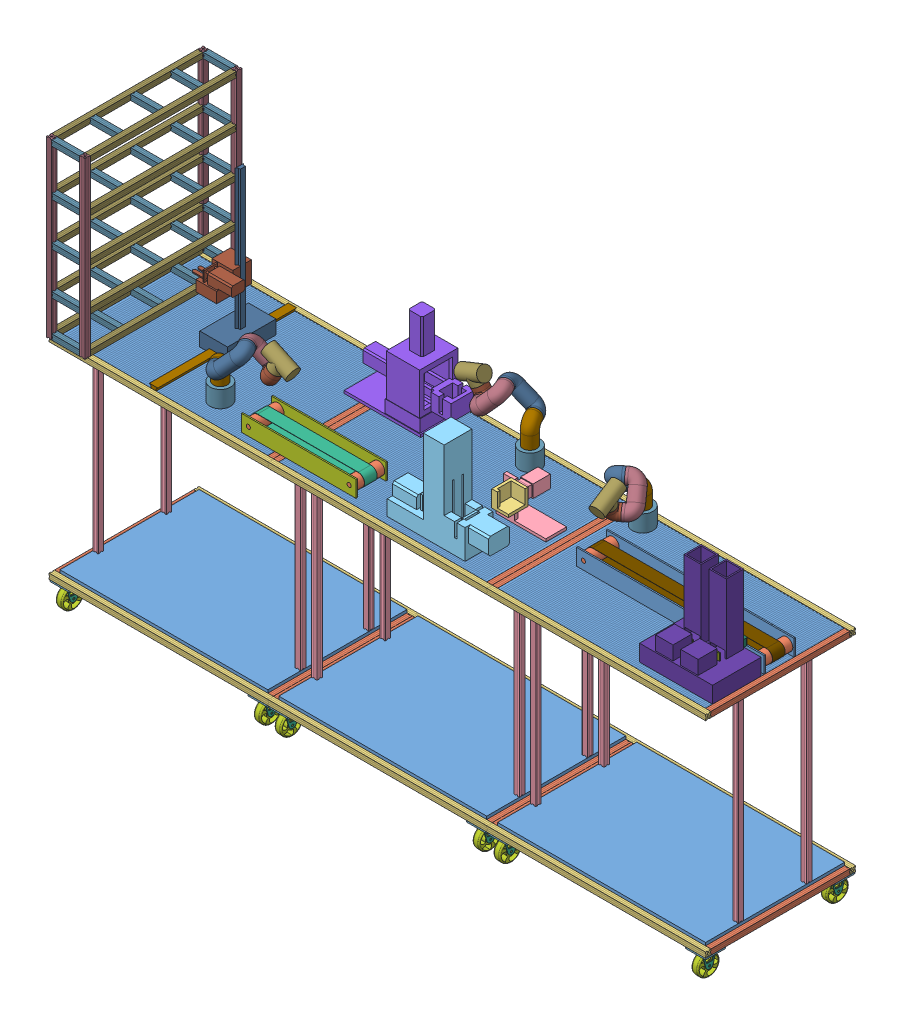
SolidWorks assembly FinalSchematic, configuration Default. Lengths in mm.
Overall size (2780.43 1698.52 1073.82).
241 component instances, 32 part files, 32 mates.
Components (placement in the parent):
- Table1-1: Table1 [Default] at (306.3244 -25.8546 100.2971) size (800.1 872.37 567.56)
  - Aluminium_Platform-1: Aluminium_Platform [Default] at (-670.8382 851.0101 977.8823) size (760.1 30.48 508.64)
  - Aluminium_Extrusion_20_03-1: Aluminium_Extrusion_20_03 [Default] at (109.2618 881.4901 978.0043) x (0 -1 0) z (1 0 0) size (20 508.76 20)
  - Aluminium_Extrusion_20_03-2: Aluminium_Extrusion_20_03 [Default] at (-670.8382 881.4901 978.0043) x (0 -1 0) z (1 0 0) size (20 508.76 20)
  - Aluminium_Extrusion_31_5-1: Aluminium_Extrusion_31_5 [Default] at (109.2618 881.4901 469.2423) x (0 0 -1) z (0 1 0) size (20 800.1 20)
  - Aluminium_Extrusion_31_5-2: Aluminium_Extrusion_31_5 [Default] at (-690.8382 861.4901 977.8823) x (0 1 0) z (0 0 -1) size (20 800.1 20)
  - Aluminium_Extrusion_28-1: Aluminium_Extrusion_28 [Default] at (69.2618 139.8101 858.1823) size (20 711.2 20)
  - Aluminium_Extrusion_28-2: Aluminium_Extrusion_28 [Default] at (69.2618 139.8101 608.9423) size (20 711.2 20)
  - Aluminium_Extrusion_28-3: Aluminium_Extrusion_28 [Default] at (-670.8382 139.8101 858.1823) size (20 711.2 20)
  - Aluminium_Extrusion_28-4: Aluminium_Extrusion_28 [Default] at (-670.8382 139.8101 608.9423) size (20 711.2 20)
  - Aluminium_Extrusion_31_5-3: Aluminium_Extrusion_31_5 [Default] at (-690.8382 129.3301 469.2423) x (0 -1 0) z (0 0 1) size (20 800.1 20)
  - Aluminium_Extrusion_31_5-4: Aluminium_Extrusion_31_5 [Default] at (109.2618 109.3301 977.8823) x (0 0 1) z (0 -1 0) size (20 800.1 20)
  - Aluminium_Extrusion_20_03-3: Aluminium_Extrusion_20_03 [Default] at (-670.8382 109.3301 469.1203) x (0 1 0) z (1 0 0) size (20 508.76 20)
  - Aluminium_Extrusion_20_03-4: Aluminium_Extrusion_20_03 [Default] at (109.2618 109.3301 469.1203) x (0 1 0) z (1 0 0) size (20 508.76 20)
  - Aluminium_Platform-2: Aluminium_Platform [Default] at (-670.8382 139.8101 469.2423) x (1 0 0) z (0 0 -1) size (760.1 30.48 508.64)
  - Assem1-1: Assem1 [Default] at (6.3509 58.2726 926.429) size (76.2 100.21 95.12)
    - Part1-1: Part1 [Default] at (64.8109 45.9775 33.3533) size (76.2 5.08 76.2)
    - Part2-1: Part2 [Default] at (64.8109 38.3575 33.3533) x (-0.998094 0 -0.06171) z (0.06171 0 -0.998094) size (30.99 63.5 50.8)
    - Part3-1: Part3 [Default] at (52.1351 -2.2825 32.5696) x (0.998094 0 0.06171) z (0.059483 -0.266209 -0.962078) size (25.4 76.2 76.2)
    - Part5-1: Part5 [Default] at (65.2258 -8.5737 26.6431) size (6.35 6.35 6.35)
    - Part5-2: Part5 [Default] at (65.3084 2.1674 25.3079) x (0.997369 0.05869 0.042559) z (0.042559 -0.949244 0.311648) size (6.35 6.35 6.35)
    - Part5-3: Part5 [Default] at (64.7035 6.7588 35.0912) x (0.993111 0.036272 0.111421) z (0.111421 -0.586665 -0.802128) size (6.35 6.35 6.35)
    - Part5-4: Part5 [Default] at (64.2471 -1.1445 42.4728) x (0.993111 -0.036272 0.111421) z (0.111421 0.586665 -0.802128) size (6.35 6.35 6.35)
    - Part5-5: Part5 [Default] at (64.5699 -10.6206 37.2516) x (0.997369 -0.05869 0.042559) z (0.042559 0.949244 0.311648) size (6.35 6.35 6.35)
  - Assem1-2: Assem1 [Default] at (-717.5491 58.2726 926.429) size (76.2 100.21 95.12)
    - Part1-1: Part1 [Default] at (64.8109 45.9775 33.3533) size (76.2 5.08 76.2)
    - Part2-1: Part2 [Default] at (64.8109 38.3575 33.3533) x (-0.998094 0 -0.06171) z (0.06171 0 -0.998094) size (30.99 63.5 50.8)
    - Part3-1: Part3 [Default] at (52.1351 -2.2825 32.5696) x (0.998094 0 0.06171) z (0.059483 -0.266209 -0.962078) size (25.4 76.2 76.2)
    - Part5-1: Part5 [Default] at (65.2258 -8.5737 26.6431) size (6.35 6.35 6.35)
    - Part5-2: Part5 [Default] at (65.3084 2.1674 25.3079) x (0.997369 0.05869 0.042559) z (0.042559 -0.949244 0.311648) size (6.35 6.35 6.35)
    - Part5-3: Part5 [Default] at (64.7035 6.7588 35.0912) x (0.993111 0.036272 0.111421) z (0.111421 -0.586665 -0.802128) size (6.35 6.35 6.35)
    - Part5-4: Part5 [Default] at (64.2471 -1.1445 42.4728) x (0.993111 -0.036272 0.111421) z (0.111421 0.586665 -0.802128) size (6.35 6.35 6.35)
    - Part5-5: Part5 [Default] at (64.5699 -10.6206 37.2516) x (0.997369 -0.05869 0.042559) z (0.042559 0.949244 0.311648) size (6.35 6.35 6.35)
  - Assem1-3: Assem1 [Default] at (-717.5491 58.2726 453.989) size (76.2 100.21 95.12)
    - Part1-1: Part1 [Default] at (64.8109 45.9775 33.3533) size (76.2 5.08 76.2)
    - Part2-1: Part2 [Default] at (64.8109 38.3575 33.3533) x (-0.998094 0 -0.06171) z (0.06171 0 -0.998094) size (30.99 63.5 50.8)
    - Part3-1: Part3 [Default] at (52.1351 -2.2825 32.5696) x (0.998094 0 0.06171) z (0.059483 -0.266209 -0.962078) size (25.4 76.2 76.2)
    - Part5-1: Part5 [Default] at (65.2258 -8.5737 26.6431) size (6.35 6.35 6.35)
    - Part5-2: Part5 [Default] at (65.3084 2.1674 25.3079) x (0.997369 0.05869 0.042559) z (0.042559 -0.949244 0.311648) size (6.35 6.35 6.35)
    - Part5-3: Part5 [Default] at (64.7035 6.7588 35.0912) x (0.993111 0.036272 0.111421) z (0.111421 -0.586665 -0.802128) size (6.35 6.35 6.35)
    - Part5-4: Part5 [Default] at (64.2471 -1.1445 42.4728) x (0.993111 -0.036272 0.111421) z (0.111421 0.586665 -0.802128) size (6.35 6.35 6.35)
    - Part5-5: Part5 [Default] at (64.5699 -10.6206 37.2516) x (0.997369 -0.05869 0.042559) z (0.042559 0.949244 0.311648) size (6.35 6.35 6.35)
  - Assem1-4: Assem1 [Default] at (6.3509 58.2726 453.989) size (76.2 100.21 95.12)
    - Part1-1: Part1 [Default] at (64.8109 45.9775 33.3533) size (76.2 5.08 76.2)
    - Part2-1: Part2 [Default] at (64.8109 38.3575 33.3533) x (-0.998094 0 -0.06171) z (0.06171 0 -0.998094) size (30.99 63.5 50.8)
    - Part3-1: Part3 [Default] at (52.1351 -2.2825 32.5696) x (0.998094 0 0.06171) z (0.059483 -0.266209 -0.962078) size (25.4 76.2 76.2)
    - Part5-1: Part5 [Default] at (65.2258 -8.5737 26.6431) size (6.35 6.35 6.35)
    - Part5-2: Part5 [Default] at (65.3084 2.1674 25.3079) x (0.997369 0.05869 0.042559) z (0.042559 -0.949244 0.311648) size (6.35 6.35 6.35)
    - Part5-3: Part5 [Default] at (64.7035 6.7588 35.0912) x (0.993111 0.036272 0.111421) z (0.111421 -0.586665 -0.802128) size (6.35 6.35 6.35)
    - Part5-4: Part5 [Default] at (64.2471 -1.1445 42.4728) x (0.993111 -0.036272 0.111421) z (0.111421 0.586665 -0.802128) size (6.35 6.35 6.35)
    - Part5-5: Part5 [Default] at (64.5699 -10.6206 37.2516) x (0.997369 -0.05869 0.042559) z (0.042559 0.949244 0.311648) size (6.35 6.35 6.35)
- Table1-2: Table1 [Default] at (-1075.3519 -25.8546 1547.4217) x (-1 0 0) z (0 0 -1) size (800.1 872.37 567.56)
  - Aluminium_Platform-1: Aluminium_Platform [Default] at (-670.8382 851.0101 977.8823) size (760.1 30.48 508.64)
  - Aluminium_Extrusion_20_03-1: Aluminium_Extrusion_20_03 [Default] at (109.2618 881.4901 978.0043) x (0 -1 0) z (1 0 0) size (20 508.76 20)
  - Aluminium_Extrusion_20_03-2: Aluminium_Extrusion_20_03 [Default] at (-670.8382 881.4901 978.0043) x (0 -1 0) z (1 0 0) size (20 508.76 20)
  - Aluminium_Extrusion_31_5-1: Aluminium_Extrusion_31_5 [Default] at (109.2618 881.4901 469.2423) x (0 0 -1) z (0 1 0) size (20 800.1 20)
  - Aluminium_Extrusion_31_5-2: Aluminium_Extrusion_31_5 [Default] at (-690.8382 861.4901 977.8823) x (0 1 0) z (0 0 -1) size (20 800.1 20)
  - Aluminium_Extrusion_28-1: Aluminium_Extrusion_28 [Default] at (69.2618 139.8101 858.1823) size (20 711.2 20)
  - Aluminium_Extrusion_28-2: Aluminium_Extrusion_28 [Default] at (69.2618 139.8101 608.9423) size (20 711.2 20)
  - Aluminium_Extrusion_28-3: Aluminium_Extrusion_28 [Default] at (-670.8382 139.8101 858.1823) size (20 711.2 20)
  - Aluminium_Extrusion_28-4: Aluminium_Extrusion_28 [Default] at (-670.8382 139.8101 608.9423) size (20 711.2 20)
  - Aluminium_Extrusion_31_5-3: Aluminium_Extrusion_31_5 [Default] at (-690.8382 129.3301 469.2423) x (0 -1 0) z (0 0 1) size (20 800.1 20)
  - Aluminium_Extrusion_31_5-4: Aluminium_Extrusion_31_5 [Default] at (109.2618 109.3301 977.8823) x (0 0 1) z (0 -1 0) size (20 800.1 20)
  - Aluminium_Extrusion_20_03-3: Aluminium_Extrusion_20_03 [Default] at (-670.8382 109.3301 469.1203) x (0 1 0) z (1 0 0) size (20 508.76 20)
  - Aluminium_Extrusion_20_03-4: Aluminium_Extrusion_20_03 [Default] at (109.2618 109.3301 469.1203) x (0 1 0) z (1 0 0) size (20 508.76 20)
  - Aluminium_Platform-2: Aluminium_Platform [Default] at (-670.8382 139.8101 469.2423) x (1 0 0) z (0 0 -1) size (760.1 30.48 508.64)
  - Assem1-1: Assem1 [Default] at (6.3509 58.2726 926.429) size (76.2 100.21 95.12)
    - Part1-1: Part1 [Default] at (64.8109 45.9775 33.3533) size (76.2 5.08 76.2)
    - Part2-1: Part2 [Default] at (64.8109 38.3575 33.3533) x (-0.998094 0 -0.06171) z (0.06171 0 -0.998094) size (30.99 63.5 50.8)
    - Part3-1: Part3 [Default] at (52.1351 -2.2825 32.5696) x (0.998094 0 0.06171) z (0.059483 -0.266209 -0.962078) size (25.4 76.2 76.2)
    - Part5-1: Part5 [Default] at (65.2258 -8.5737 26.6431) size (6.35 6.35 6.35)
    - Part5-2: Part5 [Default] at (65.3084 2.1674 25.3079) x (0.997369 0.05869 0.042559) z (0.042559 -0.949244 0.311648) size (6.35 6.35 6.35)
    - Part5-3: Part5 [Default] at (64.7035 6.7588 35.0912) x (0.993111 0.036272 0.111421) z (0.111421 -0.586665 -0.802128) size (6.35 6.35 6.35)
    - Part5-4: Part5 [Default] at (64.2471 -1.1445 42.4728) x (0.993111 -0.036272 0.111421) z (0.111421 0.586665 -0.802128) size (6.35 6.35 6.35)
    - Part5-5: Part5 [Default] at (64.5699 -10.6206 37.2516) x (0.997369 -0.05869 0.042559) z (0.042559 0.949244 0.311648) size (6.35 6.35 6.35)
  - Assem1-2: Assem1 [Default] at (-717.5491 58.2726 926.429) size (76.2 100.21 95.12)
    - Part1-1: Part1 [Default] at (64.8109 45.9775 33.3533) size (76.2 5.08 76.2)
    - Part2-1: Part2 [Default] at (64.8109 38.3575 33.3533) x (-0.998094 0 -0.06171) z (0.06171 0 -0.998094) size (30.99 63.5 50.8)
    - Part3-1: Part3 [Default] at (52.1351 -2.2825 32.5696) x (0.998094 0 0.06171) z (0.059483 -0.266209 -0.962078) size (25.4 76.2 76.2)
    - Part5-1: Part5 [Default] at (65.2258 -8.5737 26.6431) size (6.35 6.35 6.35)
    - Part5-2: Part5 [Default] at (65.3084 2.1674 25.3079) x (0.997369 0.05869 0.042559) z (0.042559 -0.949244 0.311648) size (6.35 6.35 6.35)
    - Part5-3: Part5 [Default] at (64.7035 6.7588 35.0912) x (0.993111 0.036272 0.111421) z (0.111421 -0.586665 -0.802128) size (6.35 6.35 6.35)
    - Part5-4: Part5 [Default] at (64.2471 -1.1445 42.4728) x (0.993111 -0.036272 0.111421) z (0.111421 0.586665 -0.802128) size (6.35 6.35 6.35)
    - Part5-5: Part5 [Default] at (64.5699 -10.6206 37.2516) x (0.997369 -0.05869 0.042559) z (0.042559 0.949244 0.311648) size (6.35 6.35 6.35)
  - Assem1-3: Assem1 [Default] at (-717.5491 58.2726 453.989) size (76.2 100.21 95.12)
    - Part1-1: Part1 [Default] at (64.8109 45.9775 33.3533) size (76.2 5.08 76.2)
    - Part2-1: Part2 [Default] at (64.8109 38.3575 33.3533) x (-0.998094 0 -0.06171) z (0.06171 0 -0.998094) size (30.99 63.5 50.8)
    - Part3-1: Part3 [Default] at (52.1351 -2.2825 32.5696) x (0.998094 0 0.06171) z (0.059483 -0.266209 -0.962078) size (25.4 76.2 76.2)
    - Part5-1: Part5 [Default] at (65.2258 -8.5737 26.6431) size (6.35 6.35 6.35)
    - Part5-2: Part5 [Default] at (65.3084 2.1674 25.3079) x (0.997369 0.05869 0.042559) z (0.042559 -0.949244 0.311648) size (6.35 6.35 6.35)
    - Part5-3: Part5 [Default] at (64.7035 6.7588 35.0912) x (0.993111 0.036272 0.111421) z (0.111421 -0.586665 -0.802128) size (6.35 6.35 6.35)
    - Part5-4: Part5 [Default] at (64.2471 -1.1445 42.4728) x (0.993111 -0.036272 0.111421) z (0.111421 0.586665 -0.802128) size (6.35 6.35 6.35)
    - Part5-5: Part5 [Default] at (64.5699 -10.6206 37.2516) x (0.997369 -0.05869 0.042559) z (0.042559 0.949244 0.311648) size (6.35 6.35 6.35)
  - Assem1-4: Assem1 [Default] at (6.3509 58.2726 453.989) size (76.2 100.21 95.12)
    - Part1-1: Part1 [Default] at (64.8109 45.9775 33.3533) size (76.2 5.08 76.2)
    - Part2-1: Part2 [Default] at (64.8109 38.3575 33.3533) x (-0.998094 0 -0.06171) z (0.06171 0 -0.998094) size (30.99 63.5 50.8)
    - Part3-1: Part3 [Default] at (52.1351 -2.2825 32.5696) x (0.998094 0 0.06171) z (0.059483 -0.266209 -0.962078) size (25.4 76.2 76.2)
    - Part5-1: Part5 [Default] at (65.2258 -8.5737 26.6431) size (6.35 6.35 6.35)
    - Part5-2: Part5 [Default] at (65.3084 2.1674 25.3079) x (0.997369 0.05869 0.042559) z (0.042559 -0.949244 0.311648) size (6.35 6.35 6.35)
    - Part5-3: Part5 [Default] at (64.7035 6.7588 35.0912) x (0.993111 0.036272 0.111421) z (0.111421 -0.586665 -0.802128) size (6.35 6.35 6.35)
    - Part5-4: Part5 [Default] at (64.2471 -1.1445 42.4728) x (0.993111 -0.036272 0.111421) z (0.111421 0.586665 -0.802128) size (6.35 6.35 6.35)
    - Part5-5: Part5 [Default] at (64.5699 -10.6206 37.2516) x (0.997369 -0.05869 0.042559) z (0.042559 0.949244 0.311648) size (6.35 6.35 6.35)
- Table1-3: Table1 [Default] at (-1293.8756 -25.8546 100.2971) size (800.1 872.37 567.56)
  - Aluminium_Platform-1: Aluminium_Platform [Default] at (-670.8382 851.0101 977.8823) size (760.1 30.48 508.64)
  - Aluminium_Extrusion_20_03-1: Aluminium_Extrusion_20_03 [Default] at (109.2618 881.4901 978.0043) x (0 -1 0) z (1 0 0) size (20 508.76 20)
  - Aluminium_Extrusion_20_03-2: Aluminium_Extrusion_20_03 [Default] at (-670.8382 881.4901 978.0043) x (0 -1 0) z (1 0 0) size (20 508.76 20)
  - Aluminium_Extrusion_31_5-1: Aluminium_Extrusion_31_5 [Default] at (109.2618 881.4901 469.2423) x (0 0 -1) z (0 1 0) size (20 800.1 20)
  - Aluminium_Extrusion_31_5-2: Aluminium_Extrusion_31_5 [Default] at (-690.8382 861.4901 977.8823) x (0 1 0) z (0 0 -1) size (20 800.1 20)
  - Aluminium_Extrusion_28-1: Aluminium_Extrusion_28 [Default] at (69.2618 139.8101 858.1823) size (20 711.2 20)
  - Aluminium_Extrusion_28-2: Aluminium_Extrusion_28 [Default] at (69.2618 139.8101 608.9423) size (20 711.2 20)
  - Aluminium_Extrusion_28-3: Aluminium_Extrusion_28 [Default] at (-670.8382 139.8101 858.1823) size (20 711.2 20)
  - Aluminium_Extrusion_28-4: Aluminium_Extrusion_28 [Default] at (-670.8382 139.8101 608.9423) size (20 711.2 20)
  - Aluminium_Extrusion_31_5-3: Aluminium_Extrusion_31_5 [Default] at (-690.8382 129.3301 469.2423) x (0 -1 0) z (0 0 1) size (20 800.1 20)
  - Aluminium_Extrusion_31_5-4: Aluminium_Extrusion_31_5 [Default] at (109.2618 109.3301 977.8823) x (0 0 1) z (0 -1 0) size (20 800.1 20)
  - Aluminium_Extrusion_20_03-3: Aluminium_Extrusion_20_03 [Default] at (-670.8382 109.3301 469.1203) x (0 1 0) z (1 0 0) size (20 508.76 20)
  - Aluminium_Extrusion_20_03-4: Aluminium_Extrusion_20_03 [Default] at (109.2618 109.3301 469.1203) x (0 1 0) z (1 0 0) size (20 508.76 20)
  - Aluminium_Platform-2: Aluminium_Platform [Default] at (-670.8382 139.8101 469.2423) x (1 0 0) z (0 0 -1) size (760.1 30.48 508.64)
  - Assem1-1: Assem1 [Default] at (6.3509 58.2726 926.429) size (76.2 100.21 95.12)
    - Part1-1: Part1 [Default] at (64.8109 45.9775 33.3533) size (76.2 5.08 76.2)
    - Part2-1: Part2 [Default] at (64.8109 38.3575 33.3533) x (-0.998094 0 -0.06171) z (0.06171 0 -0.998094) size (30.99 63.5 50.8)
    - Part3-1: Part3 [Default] at (52.1351 -2.2825 32.5696) x (0.998094 0 0.06171) z (0.059483 -0.266209 -0.962078) size (25.4 76.2 76.2)
    - Part5-1: Part5 [Default] at (65.2258 -8.5737 26.6431) size (6.35 6.35 6.35)
    - Part5-2: Part5 [Default] at (65.3084 2.1674 25.3079) x (0.997369 0.05869 0.042559) z (0.042559 -0.949244 0.311648) size (6.35 6.35 6.35)
    - Part5-3: Part5 [Default] at (64.7035 6.7588 35.0912) x (0.993111 0.036272 0.111421) z (0.111421 -0.586665 -0.802128) size (6.35 6.35 6.35)
    - Part5-4: Part5 [Default] at (64.2471 -1.1445 42.4728) x (0.993111 -0.036272 0.111421) z (0.111421 0.586665 -0.802128) size (6.35 6.35 6.35)
    - Part5-5: Part5 [Default] at (64.5699 -10.6206 37.2516) x (0.997369 -0.05869 0.042559) z (0.042559 0.949244 0.311648) size (6.35 6.35 6.35)
  - Assem1-2: Assem1 [Default] at (-717.5491 58.2726 926.429) size (76.2 100.21 95.12)
    - Part1-1: Part1 [Default] at (64.8109 45.9775 33.3533) size (76.2 5.08 76.2)
    - Part2-1: Part2 [Default] at (64.8109 38.3575 33.3533) x (-0.998094 0 -0.06171) z (0.06171 0 -0.998094) size (30.99 63.5 50.8)
    - Part3-1: Part3 [Default] at (52.1351 -2.2825 32.5696) x (0.998094 0 0.06171) z (0.059483 -0.266209 -0.962078) size (25.4 76.2 76.2)
    - Part5-1: Part5 [Default] at (65.2258 -8.5737 26.6431) size (6.35 6.35 6.35)
    - Part5-2: Part5 [Default] at (65.3084 2.1674 25.3079) x (0.997369 0.05869 0.042559) z (0.042559 -0.949244 0.311648) size (6.35 6.35 6.35)
    - Part5-3: Part5 [Default] at (64.7035 6.7588 35.0912) x (0.993111 0.036272 0.111421) z (0.111421 -0.586665 -0.802128) size (6.35 6.35 6.35)
    - Part5-4: Part5 [Default] at (64.2471 -1.1445 42.4728) x (0.993111 -0.036272 0.111421) z (0.111421 0.586665 -0.802128) size (6.35 6.35 6.35)
    - Part5-5: Part5 [Default] at (64.5699 -10.6206 37.2516) x (0.997369 -0.05869 0.042559) z (0.042559 0.949244 0.311648) size (6.35 6.35 6.35)
  - Assem1-3: Assem1 [Default] at (-717.5491 58.2726 453.989) size (76.2 100.21 95.12)
    - Part1-1: Part1 [Default] at (64.8109 45.9775 33.3533) size (76.2 5.08 76.2)
    - Part2-1: Part2 [Default] at (64.8109 38.3575 33.3533) x (-0.998094 0 -0.06171) z (0.06171 0 -0.998094) size (30.99 63.5 50.8)
    - Part3-1: Part3 [Default] at (52.1351 -2.2825 32.5696) x (0.998094 0 0.06171) z (0.059483 -0.266209 -0.962078) size (25.4 76.2 76.2)
    - Part5-1: Part5 [Default] at (65.2258 -8.5737 26.6431) size (6.35 6.35 6.35)
    - Part5-2: Part5 [Default] at (65.3084 2.1674 25.3079) x (0.997369 0.05869 0.042559) z (0.042559 -0.949244 0.311648) size (6.35 6.35 6.35)
    - Part5-3: Part5 [Default] at (64.7035 6.7588 35.0912) x (0.993111 0.036272 0.111421) z (0.111421 -0.586665 -0.802128) size (6.35 6.35 6.35)
    - Part5-4: Part5 [Default] at (64.2471 -1.1445 42.4728) x (0.993111 -0.036272 0.111421) z (0.111421 0.586665 -0.802128) size (6.35 6.35 6.35)
    - Part5-5: Part5 [Default] at (64.5699 -10.6206 37.2516) x (0.997369 -0.05869 0.042559) z (0.042559 0.949244 0.311648) size (6.35 6.35 6.35)
  - Assem1-4: Assem1 [Default] at (6.3509 58.2726 453.989) size (76.2 100.21 95.12)
    - Part1-1: Part1 [Default] at (64.8109 45.9775 33.3533) size (76.2 5.08 76.2)
    - Part2-1: Part2 [Default] at (64.8109 38.3575 33.3533) x (-0.998094 0 -0.06171) z (0.06171 0 -0.998094) size (30.99 63.5 50.8)
    - Part3-1: Part3 [Default] at (52.1351 -2.2825 32.5696) x (0.998094 0 0.06171) z (0.059483 -0.266209 -0.962078) size (25.4 76.2 76.2)
    - Part5-1: Part5 [Default] at (65.2258 -8.5737 26.6431) size (6.35 6.35 6.35)
    - Part5-2: Part5 [Default] at (65.3084 2.1674 25.3079) x (0.997369 0.05869 0.042559) z (0.042559 -0.949244 0.311648) size (6.35 6.35 6.35)
    - Part5-3: Part5 [Default] at (64.7035 6.7588 35.0912) x (0.993111 0.036272 0.111421) z (0.111421 -0.586665 -0.802128) size (6.35 6.35 6.35)
    - Part5-4: Part5 [Default] at (64.2471 -1.1445 42.4728) x (0.993111 -0.036272 0.111421) z (0.111421 0.586665 -0.802128) size (6.35 6.35 6.35)
    - Part5-5: Part5 [Default] at (64.5699 -10.6206 37.2516) x (0.997369 -0.05869 0.042559) z (0.042559 0.949244 0.311648) size (6.35 6.35 6.35)
- myCobotMK1-4: myCobotMK1 [Default] at (-197.0786 891.1212 591.9427) x (0.12596 0 0.992035) z (-0.992035 0 0.12596) size (284.24 251.71 208.78)
  - baseArm-1: baseArm [Default] at (6.8769 25.6643 104.8034) x (0.49795 0 0.867206) z (-0.867206 0 0.49795) size (58.2 95.42 50)
  - lowerArm-1: lowerArm [Default] at (23.4089 96.0843 133.5947) x (0.49795 0 0.867206) z (-0.601663 0.720173 0.345475) size (58.2 160.4 50)
  - pitchArm-1: pitchArm [Default] at (149.9031 103.3054 60.9616) x (0.49795 0 0.867206) z (-0.768639 0.463036 0.441353) size (58.2 65 50)
  - rollArm-1: rollArm [Default] at (150.2414 188.7187 72.416) x (0.91174 -0.410666 0.009182) z (0.086548 0.213906 0.973013) size (100 58.2 50)
  - upperArm-1: upperArm [Default] at (92.3579 172.6792 94.0041) x (-0.49795 0 -0.867206) z (-0.626681 -0.69122 0.359841) size (58.2 146 50)
  - basePlate-1: basePlate [Default] at (6.8769 -35.4857 104.8034) size (75 61.15 75)
- PneumaticProductDispenser-2: PneumaticProductDispenser [Default] at (78.0664 864.9426 1065.9834) x (-1 0 0) z (0 0 -1) size (266.7 313.94 191.3)
  - Part-1: Part [Default] at (-163.2619 50.6369 147.6192) x (1 0 0) z (0 -1 0) size (53.34 53.34 25.4)
  - PlacerRod-1: PlacerRod [Default] at (-163.2619 76.0369 98.1512) x (1 0 0) z (0 1 0) size (53.34 54.61 25.4)
  - ProductPlacer-1: ProductPlacer [Default] at (-317.5199 -9.3071 191.0041) size (266.7 313.94 177.8)
  - Part-2: Part [Default] at (-255.0495 50.6369 151.1669) x (1 0 0) z (0 -1 0) size (53.34 53.34 25.4)
  - PlacerRod-2: PlacerRod [Default] at (-255.0495 76.0369 105.6578) x (1 0 0) z (0 1 0) size (53.34 54.61 25.4)
- ConveyorAssembly-3: ConveyorAssembly [Default] at (-521.3707 517.2353 1327.2312) x (1 0 0) z (0 1 0) size (685.8 114.3 60)
  - Conveyor Belt-1: Conveyor Belt [Default] at (256.5569 496.5688 368.4002) size (682 45.72 47)
  - Conveyor Stand-1: Conveyor Stand [Default] at (231.1569 572.2188 398.4002) size (685.8 5 60)
  - Roller-1: Roller [Default] at (891.5569 520.0688 368.4002) size (45 114.3 45)
  - Roller-2: Roller [Default] at (256.5569 520.0688 368.4002) size (45 114.3 45)
  - Conveyor Stand-2: Conveyor Stand [Default] at (231.1569 462.9188 398.4002) size (685.8 5 60)
- PneumaticProductRotator-1: PneumaticProductRotator [Default] at (-369.1639 829.4952 724.7041) x (-1 0 0) z (0 0 -1) size (182.88 141.95 161.13)
  - PneumaticMotorProductHolder-1: PneumaticMotorProductHolder [Default] at (179.0828 107.1314 -120.4856) x (-1 -0.000984 0) z (0.000984 -1 0) size (60.96 70.96 60.96)
  - PneumaticMotorStand-1: PneumaticMotorStand [Default] at (53.5847 26.1402 -43.0156) size (182.88 139.7 99.06)
- PinInserterBase-1: PinInserterBase [Default] at (-509.2061 855.6355 951.1794) x (-1 0 0) z (0 0 -1) size (358.14 330.2 101.6)
- myCobotMK1-5: myCobotMK1 [Default] at (-699.9206 891.1212 731.3611) x (-0.996783 0 -0.080146) z (0.080146 0 -0.996783) size (284.24 251.71 208.78)
  - baseArm-1: baseArm [Default] at (6.8769 25.6643 104.8034) x (0.49795 0 0.867206) z (-0.867206 0 0.49795) size (58.2 95.42 50)
  - lowerArm-1: lowerArm [Default] at (23.4089 96.0843 133.5947) x (0.49795 0 0.867206) z (-0.601663 0.720173 0.345475) size (58.2 160.4 50)
  - pitchArm-1: pitchArm [Default] at (149.9031 103.3054 60.9616) x (0.49795 0 0.867206) z (-0.768639 0.463036 0.441353) size (58.2 65 50)
  - rollArm-1: rollArm [Default] at (150.2414 188.7187 72.416) x (0.91174 -0.410666 0.009182) z (0.086548 0.213906 0.973013) size (100 58.2 50)
  - upperArm-1: upperArm [Default] at (92.3579 172.6792 94.0041) x (-0.49795 0 -0.867206) z (-0.626681 -0.69122 0.359841) size (58.2 146 50)
  - basePlate-1: basePlate [Default] at (6.8769 -35.4857 104.8034) size (75 61.15 75)
- Conveyor Small-1: Conveyor Small [Default] at (-1206.4816 553.86 1244.9703) x (1 0 0) z (0 1 0) size (419.1 114.3 60)
  - Conveyor Belt_16_5-1: Conveyor Belt_16_5 [Default] at (-94.8728 225.7989 331.7755) size (415.3 45.72 47)
  - Conveyor Stand_16_5-1: Conveyor Stand_16_5 [Default] at (-120.2728 301.4909 361.7755) size (419.1 5 60)
  - Conveyor Stand_16_5-2: Conveyor Stand_16_5 [Default] at (-120.2728 192.1909 361.7755) size (419.1 5 60)
  - Roller-1: Roller [Default] at (-94.8728 249.3409 331.7755) size (45 114.3 45)
  - Roller-2: Roller [Default] at (273.4272 249.3409 331.7755) size (45 114.3 45)
- ProductBinder-1: ProductBinder [Default] at (-981.8894 855.6355 594.9394) x (-1 0 0) z (0 0 -1) size (360.72 335.12 147.32)
- myCobotMK1-6: myCobotMK1 [Default] at (-1472.8331 891.1212 885.8235) size (284.24 251.71 208.78)
  - baseArm-1: baseArm [Default] at (6.8769 25.6643 104.8034) x (0.49795 0 0.867206) z (-0.867206 0 0.49795) size (58.2 95.42 50)
  - lowerArm-1: lowerArm [Default] at (23.4089 96.0843 133.5947) x (0.49795 0 0.867206) z (-0.601663 0.720173 0.345475) size (58.2 160.4 50)
  - pitchArm-1: pitchArm [Default] at (149.9031 103.3054 60.9616) x (0.49795 0 0.867206) z (-0.768639 0.463036 0.441353) size (58.2 65 50)
  - rollArm-1: rollArm [Default] at (150.2414 188.7187 72.416) x (0.91174 -0.410666 0.009182) z (0.086548 0.213906 0.973013) size (100 58.2 50)
  - upperArm-1: upperArm [Default] at (92.3579 172.6792 94.0041) x (-0.49795 0 -0.867206) z (-0.626681 -0.69122 0.359841) size (58.2 146 50)
  - basePlate-1: basePlate [Default] at (6.8769 -35.4857 104.8034) size (75 61.15 75)
- ASRS-1: ASRS [Default] at (-1568.4223 695.9211 1482.5674) x (-0.991473 0.129665 -0.012949) z (-0.023314 -0.274272 -0.96137) size (175.49 650.11 492.58)
  - ASRSXrailing-1: ASRSXrailing [Default] at (69.6564 257.681 345.8401) x (0.991473 -0.128207 0.023314) z (-0.129665 -0.95287 0.274272) size (30.73 508 12.7)
  - ASRSXrunner-1: ASRSXrunner [Default] at (31.5718 323.2458 555.6195) x (0.012949 0.274956 0.96137) z (-0.991473 0.128207 -0.023314) size (177.8 558.8 101.6)
  - ASRSYrunner-1: ASRSYrunner [Default] at (85.4152 484.4418 500.3677) x (0.012949 0.274956 0.96137) z (-0.991473 0.128207 -0.023314) size (127 76.97 155.51)
- Rack-1: Rack [Default] at (-2150.6157 898.0243 -27.2236) x (0.57653 0.306101 -0.757572) z (0.810883 -0.100409 0.57653) size (710.4 790.88 509.16)
  - Aluminium_Extrusion_4-1: Aluminium_Extrusion_4 [Default] at (-556.3348 883.7436 734.2395) x (-0.306101 -0.946689 0.100409) z (0.57653 -0.100409 0.810883) size (20 533.4 20)
  - Aluminium_Extrusion_25-1: Aluminium_Extrusion_25 [Default] at (-346.6204 119.3218 490.4781) x (0.757572 -0.306101 -0.57653) z (0.57653 -0.100409 0.810883) size (20 635 20)
  - Aluminium_Extrusion_25-2: Aluminium_Extrusion_25 [Default] at (-765.8605 288.7181 809.5301) x (0.757572 -0.306101 -0.57653) z (0.57653 -0.100409 0.810883) size (20 635 20)
  - Aluminium_Extrusion_4-2: Aluminium_Extrusion_4 [Default] at (-703.6871 428.0226 782.575) x (-0.306101 -0.946689 0.100409) z (0.57653 -0.100409 0.810883) size (20 533.4 20)
  - Aluminium_Extrusion_4-3: Aluminium_Extrusion_4 [Default] at (-744.587 301.5299 795.9913) x (-0.306101 -0.946689 0.100409) z (0.57653 -0.100409 0.810883) size (20 533.4 20)
  - Aluminium_Extrusion_4-4: Aluminium_Extrusion_4 [Default] at (-656.4045 574.255 767.0651) x (-0.306101 -0.946689 0.100409) z (0.57653 -0.100409 0.810883) size (20 533.4 20)
  - Aluminium_Extrusion_4-5: Aluminium_Extrusion_4 [Default] at (-608.1287 723.559 751.2293) x (-0.306101 -0.946689 0.100409) z (0.57653 -0.100409 0.810883) size (20 533.4 20)
  - Aluminium_Extrusion_4-11: Aluminium_Extrusion_4 [Default] at (-633.581 415.8128 881.1783) x (-0.306101 -0.946689 0.100409) z (0.57653 -0.100409 0.810883) size (20 533.4 20)
  - Aluminium_Extrusion_4-12: Aluminium_Extrusion_4 [Default] at (-538.0226 711.3492 849.8327) x (-0.306101 -0.946689 0.100409) z (0.57653 -0.100409 0.810883) size (20 533.4 20)
  - Aluminium_Extrusion_4-13: Aluminium_Extrusion_4 [Default] at (-674.4809 289.3201 894.5946) x (-0.306101 -0.946689 0.100409) z (0.57653 -0.100409 0.810883) size (20 533.4 20)
  - Aluminium_Extrusion_4-14: Aluminium_Extrusion_4 [Default] at (-586.2984 562.0452 865.6684) x (-0.306101 -0.946689 0.100409) z (0.57653 -0.100409 0.810883) size (20 533.4 20)
  - Aluminium_Extrusion_25-7: Aluminium_Extrusion_25 [Default] at (-276.5142 107.112 589.0815) x (0.757572 -0.306101 -0.57653) z (0.57653 -0.100409 0.810883) size (20 635 20)
  - Aluminium_Extrusion_4-15: Aluminium_Extrusion_4 [Default] at (-486.2287 871.5338 832.8429) x (-0.306101 -0.946689 0.100409) z (0.57653 -0.100409 0.810883) size (20 533.4 20)
  - Aluminium_Extrusion_25-8: Aluminium_Extrusion_25 [Default] at (-695.7544 276.5083 908.1334) x (0.757572 -0.306101 -0.57653) z (0.57653 -0.100409 0.810883) size (20 635 20)
  - Aluminium_Extrusion_21-16: Aluminium_Extrusion_21 [Default] at (-99.7927 691.3339 511.1121) x (0.306101 0.946689 -0.100409) z (-0.757572 0.306101 0.57653) size (20 101.6 20)
  - Aluminium_Extrusion_21-17: Aluminium_Extrusion_21 [Default] at (-189.5655 727.6071 579.4314) x (0.306101 0.946689 -0.100409) z (-0.757572 0.306101 0.57653) size (20 101.6 20)
  - Aluminium_Extrusion_21-18: Aluminium_Extrusion_21 [Default] at (-300.8229 772.5613 664.101) x (0.306101 0.946689 -0.100409) z (-0.757572 0.306101 0.57653) size (20 101.6 20)
  - Aluminium_Extrusion_21-19: Aluminium_Extrusion_21 [Default] at (-412.8854 817.8408 749.3832) x (0.306101 0.946689 -0.100409) z (-0.757572 0.306101 0.57653) size (20 101.6 20)
  - Aluminium_Extrusion_21-20: Aluminium_Extrusion_21 [Default] at (-519.7495 861.0199 830.7094) x (0.306101 0.946689 -0.100409) z (-0.757572 0.306101 0.57653) size (20 101.6 20)
  - Aluminium_Extrusion_21-21: Aluminium_Extrusion_21 [Default] at (-570.8267 700.5456 847.1538) x (0.306101 0.946689 -0.100409) z (-0.757572 0.306101 0.57653) size (20 101.6 20)
  - Aluminium_Extrusion_21-22: Aluminium_Extrusion_21 [Default] at (-464.6793 657.6561 766.373) x (0.306101 0.946689 -0.100409) z (-0.757572 0.306101 0.57653) size (20 101.6 20)
  - Aluminium_Extrusion_21-23: Aluminium_Extrusion_21 [Default] at (-352.6168 612.3767 681.0907) x (0.306101 0.946689 -0.100409) z (-0.757572 0.306101 0.57653) size (20 101.6 20)
  - Aluminium_Extrusion_21-24: Aluminium_Extrusion_21 [Default] at (-241.3594 567.4225 596.4212) x (0.306101 0.946689 -0.100409) z (-0.757572 0.306101 0.57653) size (20 101.6 20)
  - Aluminium_Extrusion_21-25: Aluminium_Extrusion_21 [Default] at (-151.5866 531.1493 528.1019) x (0.306101 0.946689 -0.100409) z (-0.757572 0.306101 0.57653) size (20 101.6 20)
  - Aluminium_Extrusion_21-27: Aluminium_Extrusion_21 [Default] at (-178.5755 394.6985 530.3944) x (-0.306101 -0.946689 0.100409) z (0.757572 -0.306101 -0.57653) size (20 101.6 20)
  - Aluminium_Extrusion_21-28: Aluminium_Extrusion_21 [Default] at (-268.3483 430.9717 598.7137) x (-0.306101 -0.946689 0.100409) z (0.757572 -0.306101 -0.57653) size (20 101.6 20)
  - Aluminium_Extrusion_21-29: Aluminium_Extrusion_21 [Default] at (-379.6057 475.9259 683.3833) x (-0.306101 -0.946689 0.100409) z (0.757572 -0.306101 -0.57653) size (20 101.6 20)
  - Aluminium_Extrusion_21-30: Aluminium_Extrusion_21 [Default] at (-491.6682 521.2053 768.6656) x (-0.306101 -0.946689 0.100409) z (0.757572 -0.306101 -0.57653) size (20 101.6 20)
  - Aluminium_Extrusion_21-31: Aluminium_Extrusion_21 [Default] at (-597.8156 564.0948 849.4463) x (-0.306101 -0.946689 0.100409) z (0.757572 -0.306101 -0.57653) size (20 101.6 20)
  - Aluminium_Extrusion_21-57: Aluminium_Extrusion_21 [Default] at (-666.3674 405.0637 878.4937) x (0.306101 0.946689 -0.100409) z (-0.757572 0.306101 0.57653) size (20 101.6 20)
  - Aluminium_Extrusion_21-58: Aluminium_Extrusion_21 [Default] at (-560.22 362.1742 797.7129) x (0.306101 0.946689 -0.100409) z (-0.757572 0.306101 0.57653) size (20 101.6 20)
  - Aluminium_Extrusion_21-59: Aluminium_Extrusion_21 [Default] at (-448.1575 316.8947 712.4307) x (0.306101 0.946689 -0.100409) z (-0.757572 0.306101 0.57653) size (20 101.6 20)
  - Aluminium_Extrusion_21-60: Aluminium_Extrusion_21 [Default] at (-336.9001 271.9405 627.7611) x (0.306101 0.946689 -0.100409) z (-0.757572 0.306101 0.57653) size (20 101.6 20)
  - Aluminium_Extrusion_21-61: Aluminium_Extrusion_21 [Default] at (-247.1273 235.6673 559.4418) x (0.306101 0.946689 -0.100409) z (-0.757572 0.306101 0.57653) size (20 101.6 20)
  - Aluminium_Extrusion_21-67: Aluminium_Extrusion_21 [Default] at (-686.0053 291.3476 878.3749) x (-0.306101 -0.946689 0.100409) z (0.757572 -0.306101 -0.57653) size (20 101.6 20)
  - Aluminium_Extrusion_21-68: Aluminium_Extrusion_21 [Default] at (-579.8578 248.4582 797.5941) x (-0.306101 -0.946689 0.100409) z (0.757572 -0.306101 -0.57653) size (20 101.6 20)
  - Aluminium_Extrusion_21-69: Aluminium_Extrusion_21 [Default] at (-467.7954 203.1787 712.3119) x (-0.306101 -0.946689 0.100409) z (0.757572 -0.306101 -0.57653) size (20 101.6 20)
  - Aluminium_Extrusion_21-70: Aluminium_Extrusion_21 [Default] at (-356.538 158.2245 627.6423) x (-0.306101 -0.946689 0.100409) z (0.757572 -0.306101 -0.57653) size (20 101.6 20)
  - Aluminium_Extrusion_21-71: Aluminium_Extrusion_21 [Default] at (-266.7651 121.9513 559.323) x (-0.306101 -0.946689 0.100409) z (0.757572 -0.306101 -0.57653) size (20 101.6 20)
Mates (geometry in assembly coordinates):
- Coincident1: coincident aligned: plane of Table1-1/Aluminium_Extrusion_31_5-1 through (-384.5137 855.6355 549.5394) normal (0 0 -1); plane of Table1-2/Aluminium_Extrusion_31_5-2 through (-1184.6137 835.6355 549.5394) normal (0 0 -1)
- Coincident2: coincident anti-aligned: plane of Table1-1/Aluminium_Extrusion_20_03-2 through (-384.5137 855.6355 569.5394) normal (-1 0 0); plane of Table1-2/Aluminium_Extrusion_20_03-2 through (-384.5137 855.6355 1078.1794) normal (1 0 0)
- Coincident3: coincident aligned: plane of Table1-2/Aluminium_Extrusion_31_5-1 through (-384.5137 855.6355 1098.1794) normal (0 0 1); plane of Table1-3/Aluminium_Extrusion_31_5-2 through (-1184.6137 835.6355 1098.1794) normal (0 0 1)
- Coincident4: coincident anti-aligned: plane of Table1-2/Aluminium_Extrusion_20_03-1 through (-1184.6137 855.6355 1078.1794) normal (-1 0 0); plane of Table1-3/Aluminium_Extrusion_20_03-1 through (-1184.6137 855.6355 569.5394) normal (1 0 0)
- Coincident5: coincident aligned: plane of Table1-1/Aluminium_Platform-1 through (-364.5137 825.1555 1078.1794) normal (0 -1 0); plane of Table1-2/Aluminium_Platform-1 through (-404.5137 825.1555 569.5394) normal (0 -1 0)
- Coincident6: coincident aligned: plane of Table1-2/Aluminium_Platform-1 through (-404.5137 825.1555 569.5394) normal (0 -1 0); plane of Table1-3/Aluminium_Platform-1 through (-1964.7137 825.1555 1078.1794) normal (0 -1 0)
- Coincident7: coincident anti-aligned: plane of Table1-1/Aluminium_Extrusion_31_5-1 through (-384.5137 855.6355 569.5394) normal (0 1 0); plane of myCobotMK1-4/basePlate-1 through (-300.1811 855.6355 611.9659) normal (0 -1 0)
- Coincident8: coincident anti-aligned: plane of Table1-1/Aluminium_Extrusion_31_5-2 through (415.5863 855.6355 1078.1794) normal (0 1 0); plane of PneumaticProductDispenser-2/ProductPlacer-1 through (395.5863 855.6355 874.9794) normal (0 -1 0)
- Distance1: distance = 25.4 mm: line of Table1-1/Aluminium_Platform-1 through (338.3475 855.6355 1078.1794) axis (1 0 0); plane of PneumaticProductDispenser-2/ProductPlacer-1 through (395.5863 915.5795 1052.7794) normal (0 0 1)
- Coincident12: coincident: line of Table1-1/Aluminium_Platform-1 through (395.5863 855.6355 1078.1794) axis (0 0 -1); plane of PneumaticProductDispenser-2/ProductPlacer-1 through (395.5863 915.5795 874.9794) normal (1 0 0)
- Coincident13: coincident anti-aligned: plane of Table1-1/Aluminium_Platform-1 through (-364.5137 855.6355 1078.1794) normal (0 1 0); plane of ConveyorAssembly-3/Conveyor Stand-1 through (-290.2137 855.6355 750.0124) normal (0 -1 0)
- Coincident14: coincident: line of Table1-1/Aluminium_Platform-1 through (395.5863 855.6355 1078.1794) axis (0 0 -1); plane of ConveyorAssembly-3/Conveyor Stand-2 through (395.5863 915.6355 859.3124) normal (1 0 0)
- Distance2: distance = 10.667 mm anti-aligned: plane of PneumaticProductDispenser-2/ProductPlacer-1 through (395.5863 915.5795 874.9794) normal (0 0 -1); plane of ConveyorAssembly-3/Conveyor Stand-2 through (-290.2137 915.6355 864.3124) normal (0 0 1)
- Coincident16: coincident anti-aligned: plane of Table1-2/Aluminium_Platform-1 through (-404.5137 855.6355 569.5394) normal (0 1 0); plane of PneumaticProductRotator-1/PneumaticMotorStand-1 through (-422.7486 855.6355 767.7197) normal (0 -1 0)
- Coincident17: coincident anti-aligned: plane of Table1-2/Aluminium_Platform-1 through (-404.5137 855.6355 569.5394) normal (0 1 0); plane of PinInserterBase-1 through (-509.2061 855.6355 951.1794) normal (0 -1 0)
- Distance3: distance = 25.4 mm: line of Table1-2/Aluminium_Platform-1 through (-558.9889 855.6355 1078.1794) axis (1 0 0); plane of PinInserterBase-1 through (-509.2061 911.5155 1052.7794) normal (0 0 1)
- Distance4: distance = 107.2597 mm anti-aligned: plane of PneumaticProductRotator-1/PneumaticMotorStand-1 through (-422.7486 865.6355 843.9197) normal (0 0 1); plane of PinInserterBase-1 through (-509.2061 911.5155 951.1794) normal (0 0 -1)
- Coincident20: coincident anti-aligned: plane of Table1-2/Aluminium_Platform-1 through (-404.5137 855.6355 569.5394) normal (0 1 0); plane of myCobotMK1-5/basePlate-1 through (-698.3759 855.6355 626.3436) normal (0 -1 0)
- Coincident21: coincident anti-aligned: plane of Table1-2/Aluminium_Platform-1 through (-404.5137 855.6355 569.5394) normal (0 1 0); plane of Conveyor Small-1/Conveyor Stand_16_5-1 through (-1326.7544 855.6355 938.4794) normal (0 -1 0)
- Coincident22: coincident aligned: plane of PinInserterBase-1 through (-509.2061 911.5155 1052.7794) normal (0 0 1); plane of Conveyor Small-1/Conveyor Stand_16_5-2 through (-1326.7544 915.6355 1052.7794) normal (0 0 1)
- Distance5: distance = 113.9683 mm anti-aligned: plane of Conveyor Small-1/Conveyor Stand_16_5-2 through (-907.6544 915.6355 1047.7794) normal (1 0 0); plane of PinInserterBase-1 through (-793.6861 911.5155 951.1794) normal (-1 0 0)
- Coincident24: coincident anti-aligned: plane of Table1-2/Aluminium_Platform-1 through (-404.5137 855.6355 569.5394) normal (0 1 0); plane of ProductBinder-1 through (-981.8894 855.6355 594.9394) normal (0 -1 0)
- Distance6: distance = 25.4 mm: line of Table1-2/Aluminium_Platform-1 through (-1133.7909 855.6355 569.5394) axis (-1 0 0); plane of ProductBinder-1 through (-981.8894 865.6355 594.9394) normal (0 0 -1)
- Coincident27: coincident anti-aligned: plane of Table1-3/Aluminium_Platform-1 through (-1964.7137 855.6355 1078.1794) normal (0 1 0); plane of myCobotMK1-6/basePlate-1 through (-1465.9562 855.6355 990.6269) normal (0 -1 0)
- Coincident28: coincident anti-aligned: plane of Table1-3/Aluminium_Platform-1 through (-1964.7137 855.6355 1078.1794) normal (0 1 0); plane of ASRS-1/ASRSXrailing-1 through (-1612.5111 855.6355 570.3344) normal (0 -1 0)
- Distance7: distance = 5.08 mm: line of Table1-3/Aluminium_Extrusion_31_5-1 through (-1984.7137 853.2538 565.2544) axis (1 0 0); plane of ASRS-1/ASRSXrailing-1 through (-1612.5111 855.6355 570.3344) normal (0 0 -1)
- Coincident30: coincident anti-aligned: plane of Table1-3/Aluminium_Platform-1 through (-1964.7137 855.6355 1078.1794) normal (0 1 0); plane of Rack-1/Aluminium_Extrusion_25-2 through (-1964.7137 855.6355 1108.0662) normal (0 -1 0)
- Coincident31: coincident aligned: plane of Table1-3/Aluminium_Extrusion_20_03-2 through (-1984.7137 855.6355 569.5394) normal (-1 0 0); plane of Rack-1/Aluminium_Extrusion_25-2 through (-1984.7137 1490.6355 1108.0662) normal (-1 0 0)
- Distance8: distance = 9.8868 mm aligned: plane of Rack-1/Aluminium_Extrusion_25-2 through (-1964.7137 1490.6355 1108.0662) normal (0 0 1); plane of Table1-3/Aluminium_Extrusion_31_5-2 through (-1184.6137 835.6355 1098.1794) normal (0 0 1)
- Distance9: distance = 42.4265 mm: cylinder of myCobotMK1-4/basePlate-1 through (-300.1811 916.7855 611.9659) axis (0 -1 0) radius 37.5; line of Table1-1/Aluminium_Platform-1 through (-276.0785 855.6355 569.5394) axis (-1 0 0)
- Distance10: distance = 64.3327 mm: cylinder of myCobotMK1-4/basePlate-1 through (-300.1811 916.7855 611.9659) axis (0 -1 0) radius 37.5; line of Table1-1/Aluminium_Platform-1 through (-364.5137 855.6355 569.5394) axis (0 0 1)
- Distance11: distance = 56.8043 mm: cylinder of myCobotMK1-5/basePlate-1 through (-698.3759 916.7855 626.3436) axis (0 -1 0) radius 37.5; line of Table1-2/Aluminium_Platform-1 through (-803.5909 855.6355 569.5394) axis (-1 0 0)
